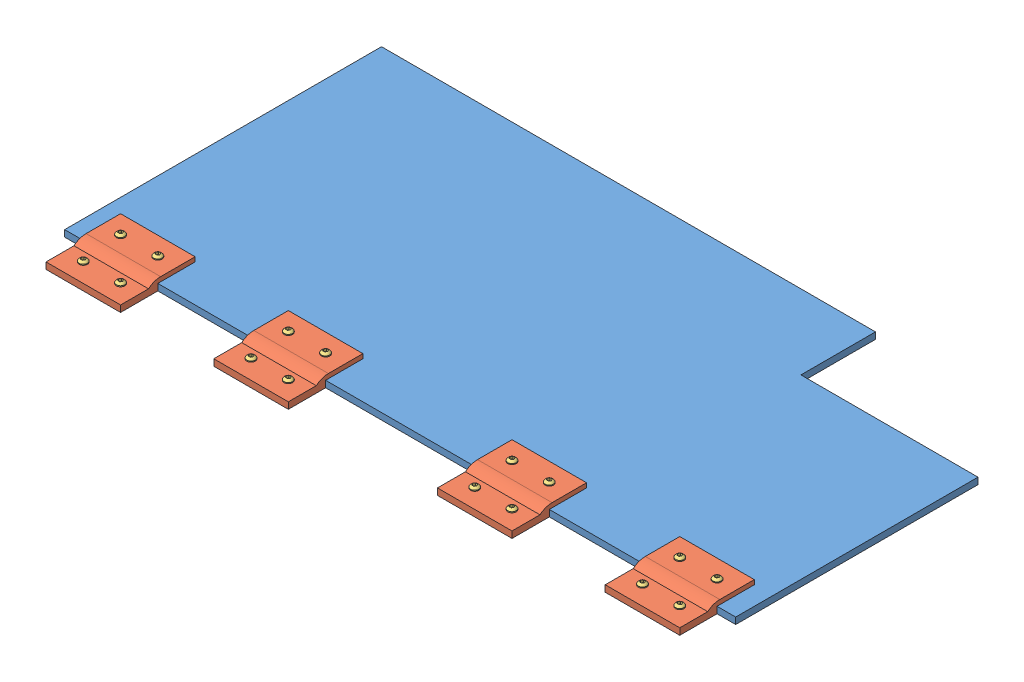
SolidWorks assembly Enclosure_right_side, configuration Default. Lengths in mm.
Overall size (360 12.64 195).
37 component instances, 5 part files, 0 mates.
Components (placement in the parent):
- Right_plexiglass_panel-1: Right_plexiglass_panel [Default] at (-180 0 0) size (360 3.5 170)
- Enclosure_holder-1: Enclosure_holder [Default] at (-170 0 20) size (40 5.5 25)
- M3x8-1: M3x8 [Default] at (-160 5.9 -10) size (4.5 9.55 4.5)
- M3x8-2: M3x8 [Default] at (-140 5.9 -10) size (4.5 9.55 4.5)
- M3x8-3: M3x8 [Default] at (-140 3.5 10) size (4.5 9.55 4.5)
- M3x8-4: M3x8 [Default] at (-160 3.5 10) size (4.5 9.55 4.5)
- M3_nut-1: M3_nut [Default] at (-160 0 -10) x (1 0 0) z (0 0 -1) size (5.5 2.58 6.35)
- M3_nut-2: M3_nut [Default] at (-140 0 -10) x (1 0 0) z (0 0 -1) size (5.5 2.58 6.35)
- M3_t_nut-1: M3_t_nut [Default] at (-160 -5 10) x (0 0 -1) z (1 0 0) size (10 5.19 6)
- M3_t_nut-3: M3_t_nut [Default] at (-140 -5 10) x (0 0 -1) z (1 0 0) size (10 5.19 6)
- M3_t_nut-4: M3_t_nut [Default] at (-50 -5 10) x (0 0 -1) z (1 0 0) size (10 5.19 6)
- M3_t_nut-5: M3_t_nut [Default] at (-70 -5 10) x (0 0 -1) z (1 0 0) size (10 5.19 6)
- M3_nut-3: M3_nut [Default] at (-50 0 -10) x (1 0 0) z (0 0 -1) size (5.5 2.58 6.35)
- M3_nut-4: M3_nut [Default] at (-70 0 -10) x (1 0 0) z (0 0 -1) size (5.5 2.58 6.35)
- M3x8-5: M3x8 [Default] at (-70 3.5 10) size (4.5 9.55 4.5)
- M3x8-6: M3x8 [Default] at (-50 3.5 10) size (4.5 9.55 4.5)
- M3x8-7: M3x8 [Default] at (-50 5.9 -10) size (4.5 9.55 4.5)
- M3x8-8: M3x8 [Default] at (-70 5.9 -10) size (4.5 9.55 4.5)
- Enclosure_holder-2: Enclosure_holder [Default] at (-80 0 20) size (40 5.5 25)
- Enclosure_holder-3: Enclosure_holder [Default] at (40 0 20) size (40 5.5 25)
- M3x8-9: M3x8 [Default] at (50 5.9 -10) x (-1 0 0) z (0 0 -1) size (4.5 9.55 4.5)
- M3_t_nut-6: M3_t_nut [Default] at (50 -0.1867 10) x (0 0 -1) z (-1 0 0) size (10 5.19 6)
- M3_nut-5: M3_nut [Default] at (50 0 -10) x (-1 0 0) z (0 0 1) size (5.5 2.58 6.35)
- M3x8-10: M3x8 [Default] at (70 3.5 10) x (-1 0 0) z (0 0 -1) size (4.5 9.55 4.5)
- M3x8-11: M3x8 [Default] at (50 3.5 10) x (-1 0 0) z (0 0 -1) size (4.5 9.55 4.5)
- M3_nut-6: M3_nut [Default] at (70 0 -10) x (-1 0 0) z (0 0 1) size (5.5 2.58 6.35)
- M3x8-12: M3x8 [Default] at (70 5.9 -10) x (-1 0 0) z (0 0 -1) size (4.5 9.55 4.5)
- M3_t_nut-7: M3_t_nut [Default] at (70 -0.1867 10) x (0 0 -1) z (-1 0 0) size (10 5.19 6)
- M3_nut-7: M3_nut [Default] at (160 0 -10) x (-1 0 0) z (0 0 1) size (5.5 2.58 6.35)
- M3_nut-8: M3_nut [Default] at (140 0 -10) x (-1 0 0) z (0 0 1) size (5.5 2.58 6.35)
- M3_t_nut-8: M3_t_nut [Default] at (140 -0.1867 10) x (0 0 -1) z (-1 0 0) size (10 5.19 6)
- M3x8-13: M3x8 [Default] at (140 5.9 -10) x (-1 0 0) z (0 0 -1) size (4.5 9.55 4.5)
- M3x8-14: M3x8 [Default] at (160 3.5 10) x (-1 0 0) z (0 0 -1) size (4.5 9.55 4.5)
- Enclosure_holder-4: Enclosure_holder [Default] at (130 0 20) size (40 5.5 25)
- M3x8-15: M3x8 [Default] at (160 5.9 -10) x (-1 0 0) z (0 0 -1) size (4.5 9.55 4.5)
- M3_t_nut-9: M3_t_nut [Default] at (160 -0.1867 10) x (0 0 -1) z (-1 0 0) size (10 5.19 6)
- M3x8-16: M3x8 [Default] at (140 3.5 10) x (-1 0 0) z (0 0 -1) size (4.5 9.55 4.5)
